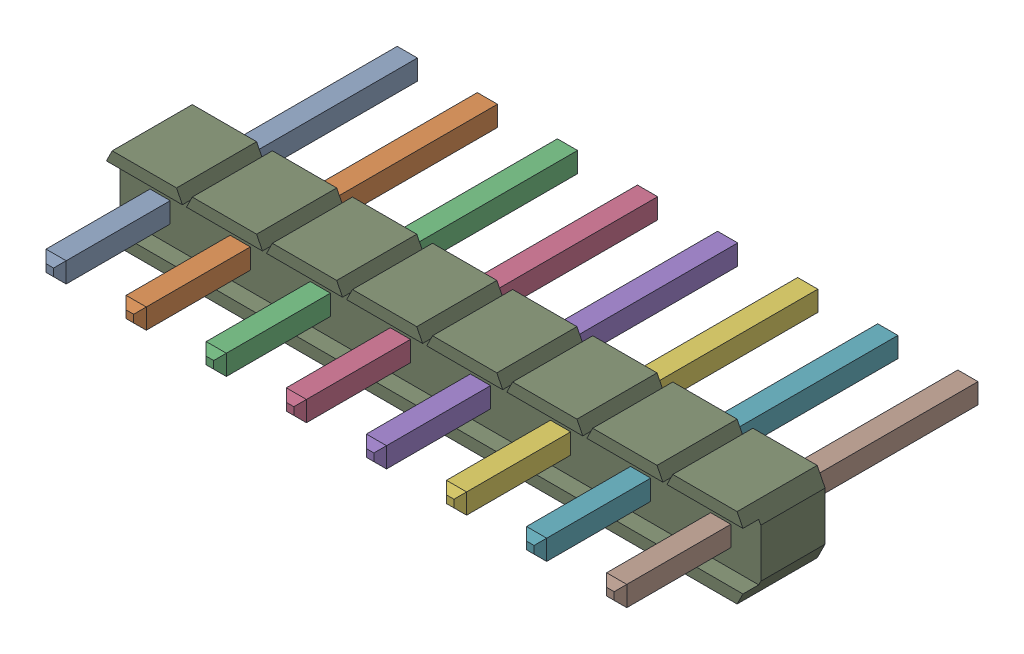
SolidWorks assembly C1_1, configuration Default. Lengths in mm.
Overall size (20.32 2.54 11.54).
10 component instances, 2 part files, 0 mates.
Components (placement in the parent):
- 61300811121-1: 61300811121 [Default] at (23.5001 29.2999 -1.6815) x (1 0 0) z (0 1 0) size (20.32 11.54 2.54)
  - 6130xx11121_PIN_2-1: 6130xx11121_PIN_2 [Default] at (-8.89 1.5 0) x (1 0 0) z (0 -1 0) size (0.64 0.64 11.54)
  - 6130xx11121_PIN_2-2: 6130xx11121_PIN_2 [Default] at (-6.35 1.5 0) x (1 0 0) z (0 -1 0) size (0.64 0.64 11.54)
  - 6130xx11121_PIN_2-3: 6130xx11121_PIN_2 [Default] at (-3.81 1.5 0) x (1 0 0) z (0 -1 0) size (0.64 0.64 11.54)
  - 6130xx11121_PIN_2-4: 6130xx11121_PIN_2 [Default] at (-1.27 1.5 0) x (1 0 0) z (0 -1 0) size (0.64 0.64 11.54)
  - 6130xx11121_PIN_2-5: 6130xx11121_PIN_2 [Default] at (1.27 1.5 0) x (1 0 0) z (0 -1 0) size (0.64 0.64 11.54)
  - 6130xx11121_PIN_2-6: 6130xx11121_PIN_2 [Default] at (3.81 1.5 0) x (1 0 0) z (0 -1 0) size (0.64 0.64 11.54)
  - 6130xx11121_PIN_2-7: 6130xx11121_PIN_2 [Default] at (6.35 1.5 0) x (1 0 0) z (0 -1 0) size (0.64 0.64 11.54)
  - 6130xx11121_PIN_2-8: 6130xx11121_PIN_2 [Default] at (8.89 1.5 0) x (1 0 0) z (0 -1 0) size (0.64 0.64 11.54)
  - 61300811121-1: 61300811121 [Default] at origin size (20.32 2.54 2.54)
